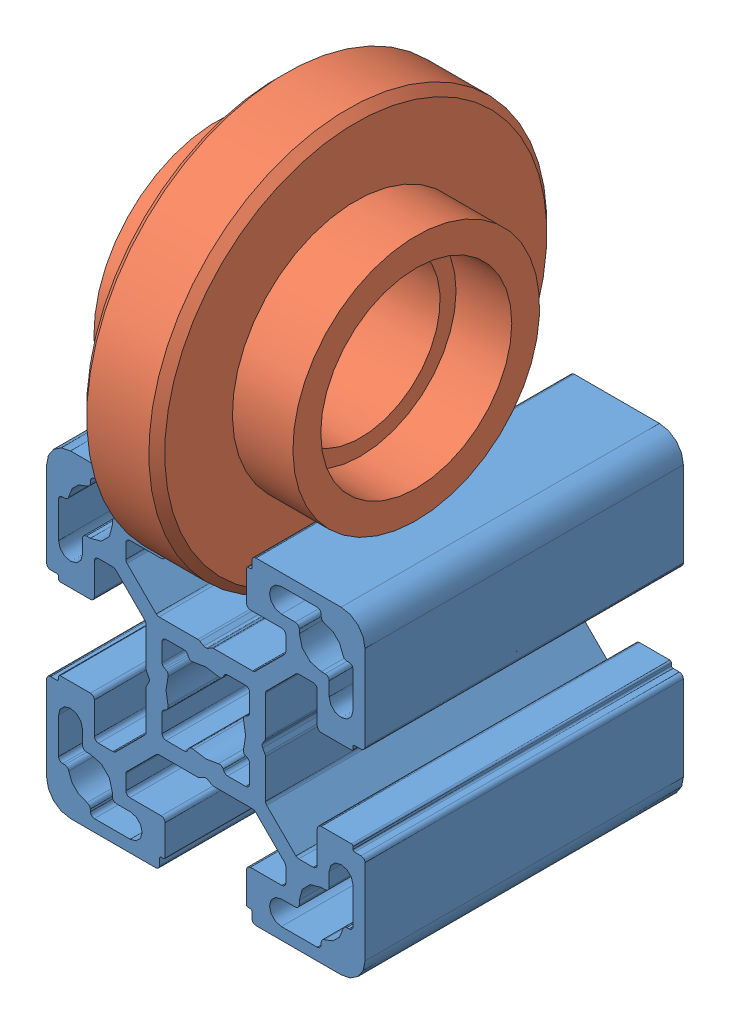
SolidWorks assembly Ролик 10паз СБ, configuration По умолчанию. Lengths in mm.
Overall size (40 84.37 57.73).
2 component instances, 2 part files, 2 mates.
Components (placement in the parent):
- 40х40х100-1: 40х40х100 [По умолчанию] at origin size (40 40 40)
- Ролик 10 паз-1: Ролик 10 паз [По умолчанию] at (-0.2 35.5 25.8598) x (1 0 0) z (0 -0.169084 0.985602) size (25 50 50)
Mates (geometry in assembly coordinates):
- Совпадение1: coincident anti-aligned: plane of 40х40х100-1 through (-5.1 0 40) normal (1 0 0); plane of Ролик 10 паз-1 through (-5.1 50.7768 28.4806) normal (-1 0 0)
- Касательность1: tangent anti-aligned: plane of 40х40х100-1 through (0 20 40) normal (0 1 0); cylinder of Ролик 10 паз-1 through (-24.8188 35.5 25.8598) axis (-1 0 0) radius 15.5
